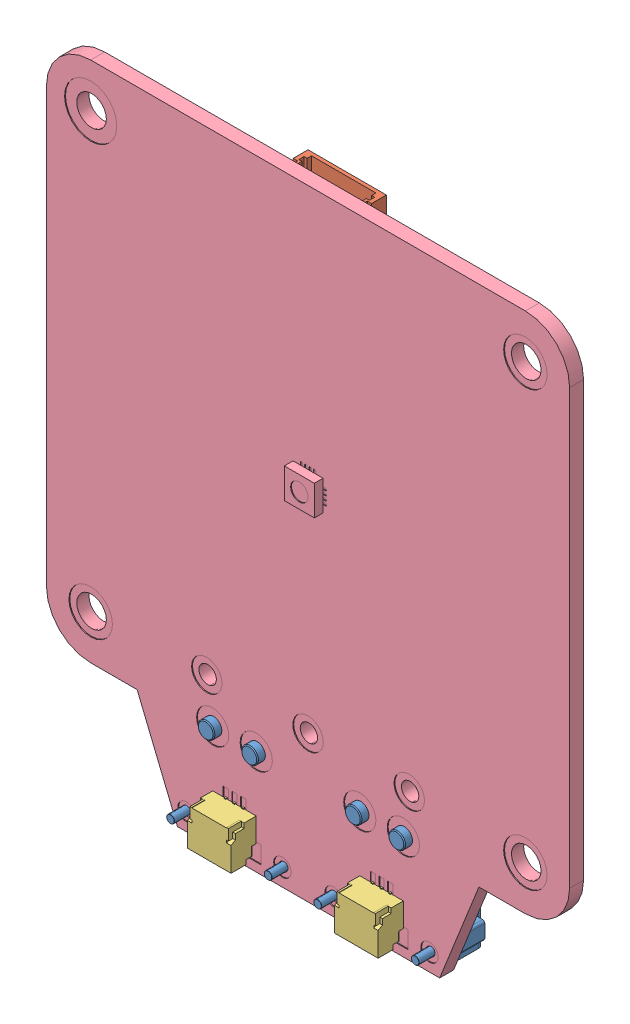
SolidWorks assembly LAIKA_Driver, configuration Default. Lengths in mm.
Overall size (60.07 72.26 9.64).
6 component instances, 4 part files, 19 mates.
Components (placement in the parent):
- XT30-2: XT30 [Default] at (8.4454 -33.29 -2.6) x (-1 0 0) z (0 0 -1) size (13.3 13.95 8.49)
- XT30-3: XT30 [Default] at (-8.4456 -33.29 -2.6) x (-1 0 0) z (0 0 -1) size (13.3 13.95 8.49)
- JST 7-1: JST 7 [Default] at (0 24.7735 -2.2) size (9 4.32 3.6)
- JST 3-1: JST 3 [Default] at (-8.4455 -35.6955 3.8) x (1 0 0) z (0 0 -1) size (5 4.32 3.6)
- JST 3-2: JST 3 [Default] at (8.4455 -35.6955 3.8) x (1 0 0) z (0 0 -1) size (5 4.32 3.6)
- LAIKA_Driver_Board-4: LAIKA_Driver_Board [Default] at origin size (60.07 71.25 3.6)
Mates (geometry in assembly coordinates):
- Concentric1: concentric: cylinder of LAIKA_Driver_Board-4 through (-10.9456 -29.29 1.6) axis (0 0 -1) radius 0.85; cylinder of XT30-3 through (-10.9456 -29.29 2.4) axis (0 0 -1) radius 0.95
- Coincident1: coincident: plane of LAIKA_Driver_Board-4 through (-24.9555 24.892 0) normal (0 0 -1); plane of XT30-3 through (-8.4456 -33.29 0) normal (0 0 1)
- Concentric2: concentric: cylinder of LAIKA_Driver_Board-4 through (5.9454 -29.29 1.6) axis (0 0 -1) radius 0.85; cylinder of XT30-2 through (5.9454 -29.29 2.4) axis (0 0 -1) radius 0.95
- Coincident2: coincident: plane of LAIKA_Driver_Board-4 through (-24.9555 24.892 0) normal (0 0 -1); plane of XT30-2 through (8.4454 -33.29 0) normal (0 0 1)
- InPlace1: in place: plane of LAIKA_Driver_Board-4 through (-24.9555 24.892 1.6) normal (0 0 1); plane of ? through (0 0 1.6) normal (0 0 1); moOrthogonalPlaneRef_w of LAIKA_Driver_Board-4 through (-24.9555 24.892 1.6) normal (0 0 1); plane of ? through (0 0 1.6) normal (0 1 0); plane of LAIKA_Driver_Board-4 through (-24.9555 24.892 1.6) normal (0 0 1); plane of ? through (0 0 1.6) normal (1 0 0); plane of LAIKA_Driver_Board-4 through (-24.9555 24.892 1.6) normal (0 0 1); unknown of ?
- Coincident3: coincident: plane of ?; plane of ?
- Coincident4: coincident: moOrthogonalPlaneRef_w of LAIKA_Driver_Board-4 through (0 0 1.6) normal (0 1 0); plane of ? through (0 0 1.6) normal (0 1 0)
- Coincident5: coincident: moOrthogonalPlaneRef_w of LAIKA_Driver_Board-4 through (0 0 1.6) normal (-1 0 0); plane of ? through (0 0 1.6) normal (1 0 0)
- Coincident3: coincident: plane of LAIKA_Driver_Board-4 through (-24.9555 24.892 0) normal (0 0 -1); plane of JST 7-1 through (-4.5 24.7735 0) normal (0 0 1)
- Distance1: distance = 1 mm anti-aligned: plane of JST 7-1 through (-3.1 24.7035 -0.1) normal (0 -1 0); plane of LAIKA_Driver_Board-4 through (-2.7 23.7035 0.1) normal (0 1 0)
- Distance2: distance = 0.2 mm anti-aligned: plane of JST 7-1 through (-3.1 25.3235 0.7) normal (-1 0 0); plane of LAIKA_Driver_Board-4 through (-3.3 25.2535 0.1) normal (1 0 0)
- Coincident6: coincident: plane of LAIKA_Driver_Board-4 through (-24.9555 24.892 1.6) normal (0 0 1); plane of JST 3-1 through (-10.9455 -39.9455 1.6) normal (0 0 -1)
- Coincident7: coincident: plane of LAIKA_Driver_Board-4 through (-24.9555 24.892 1.6) normal (0 0 1); plane of JST 3-2 through (5.9455 -39.9455 1.6) normal (0 0 -1)
- Distance3: distance = 1 mm anti-aligned: plane of JST 3-2 through (9.3455 -35.6255 1.7) normal (0 1 0); plane of LAIKA_Driver_Board-4 through (9.1455 -34.6255 1.5) normal (0 -1 0)
- Distance4: distance = 1 mm anti-aligned: plane of JST 3-1 through (-7.5455 -35.6255 1.7) normal (0 1 0); plane of LAIKA_Driver_Board-4 through (-7.7455 -34.6255 1.5) normal (0 -1 0)
- Distance5: distance = 0.2 mm: plane of JST 3-2 through (9.5455 -36.2455 0.9) normal (1 0 0); line of LAIKA_Driver_Board-4 through (9.7455 -36.1755 1.5) axis (0 1 0)
- Distance6: distance = 0.2 mm anti-aligned: plane of JST 3-1 through (-7.3455 -36.2455 0.9) normal (1 0 0); plane of LAIKA_Driver_Board-4 through (-7.1455 -34.6255 1.5) normal (-1 0 0)
- Concentric3: concentric aligned: cylinder of XT30-3 through (-10.9456 -29.29 2.4) axis (0 0 -1) radius 0.95; cylinder of LAIKA_Driver_Board-4 through (-10.9456 -29.29 1.6) axis (0 0 -1) radius 0.85
- Coincident8: coincident: line of XT30-3 through (-12.9956 -40.19 0) axis (-1 0 0); plane of LAIKA_Driver_Board-4 through (-24.9555 24.892 0) normal (0 0 -1)
